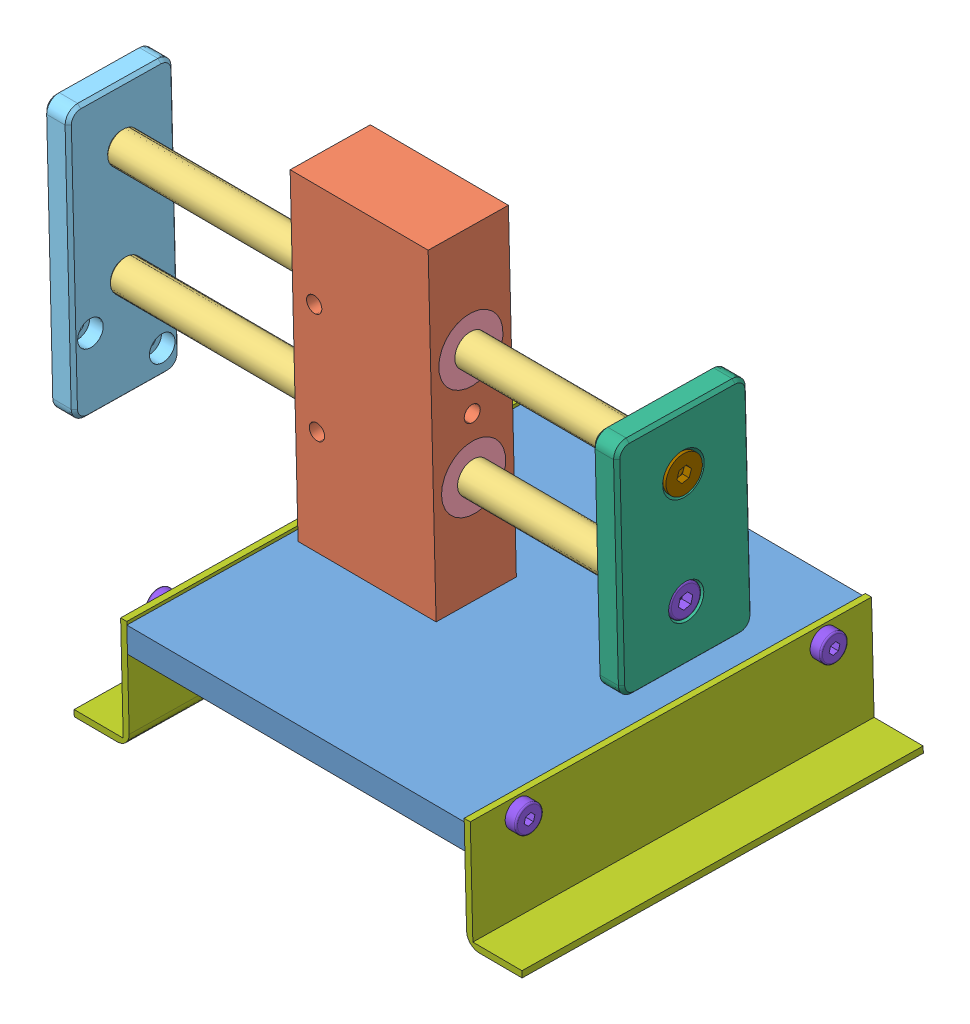
SolidWorks assembly cum s1, configuration Default. Lengths in mm.
Overall size (205.02 137.7 128.52).
22 component instances, 9 part files, 49 mates.
Components (placement in the parent):
- tam de lon-1: tam de lon [Default] at (119.0958 51.1975 54.0073) x (-0.999587 -0.017639 -0.022689) z (-0.022562 -0.007384 0.999718) size (110 8 125)
- con truot s1-2: con truot s1 [Default] at (88.5768 136.6703 53.9498) x (0.999587 0.017639 0.022689) z (0.022562 0.007384 -0.999718) size (45 102 25)
- chot dan huong-1: chot dan huong [Default] at (-2.2614 117.565 51.7586) x (0.021471 -0.983136 -0.181614) z (-0.019103 -0.182026 0.983108) size (10 175 10)
- chot dan huong-2: chot dan huong [Default] at (-1.6384 82.5714 51.5142) x (0.026236 -0.237789 -0.970963) z (0.011731 -0.971157 0.238153) size (10 175 10)
- bac lot-1: bac lot [Default] at (66.3976 118.7766 53.3171) x (0.028076 -0.767933 -0.639915) z (-0.006137 -0.640287 0.768111) size (20 12 20)
- bac lot-2: bac lot [Default] at (67.0207 83.783 53.0727) x (0.018145 -0.999587 -0.022287) z (-0.022287 -0.022689 0.999494) size (20 12 20)
- bac lot-3: bac lot [Default] at (111.379 119.5704 54.3381) x (-0.014484 -0.372719 0.927831) z (0.024823 -0.927776 -0.37231) size (20 12 20)
- bac lot-4: bac lot [Default] at (112.0021 84.5768 54.0937) x (-0.014484 -0.372719 0.927831) z (0.024823 -0.927776 -0.37231) size (20 12 20)
- ban canh truoc-1: ban canh truoc [Default] at (-1.8075 92.0697 51.5805) x (-0.022562 -0.007384 0.999718) z (0.017801 -0.999817 -0.006983) size (33 8 86)
- ban canh sau -S1-1: ban canh sau -S1 [Default] at (172.9778 103.155 55.607) x (-0.022562 -0.007384 0.999718) z (-0.017801 0.999817 0.006983) size (41 8 70)
- khoi do-1: khoi do [Default] at (173.7917 36.5109 117.6508) x (0.022562 0.007384 -0.999718) z (-0.999587 -0.017639 -0.022689) size (125 35 18)
- khoi do-2: khoi do [Default] at (64.9414 35.4633 -9.8487) x (-0.022562 -0.007384 0.999718) z (0.999587 0.017639 0.022689) size (125 35 18)
- socket head thin cap screw_din-2: socket head thin cap screw_din [DIN 7984 - M5 x 12 --- 9.6N] at (57.6203 45.7804 100.0932) x (0.999587 0.017639 0.022689) z (-0.022689 -0.0002 0.999743) size (15.5 8.5 8.5)
- socket head thin cap screw_din-3: socket head thin cap screw_din [DIN 7984 - M5 x 12 --- 9.6N] at (59.7637 46.4818 5.12) x (0.999587 0.017639 0.022689) z (-0.022689 -0.0002 0.999743) size (15.5 8.5 8.5)
- socket head thin cap screw_din-4: socket head thin cap screw_din [DIN 7984 - M5 x 12 --- 9.6N] at (180.7137 48.6161 7.8654) x (-0.999587 -0.017639 -0.022689) z (0.022689 -0.968916 -0.246346) size (15.5 8.5 8.5)
- socket head thin cap screw_din-5: socket head thin cap screw_din [DIN 7984 - M5 x 12 --- 9.6N] at (178.5703 47.9147 102.8386) x (-0.999587 -0.017639 -0.022689) z (0.022689 -0.968916 -0.246346) size (15.5 8.5 8.5)
- socket head thin cap screw_din-6: socket head thin cap screw_din [DIN 7984 - M5 x 12 --- 9.6N] at (108.0343 45.1492 61.2151) x (-0.017801 0.999817 0.006983) z (-0.006983 -0.007108 0.99995) size (15.5 8.5 8.5)
- socket head thin cap screw_din-7: socket head thin cap screw_din [DIN 7984 - M5 x 12 --- 9.6N] at (72.3876 44.6249 45.4025) x (-0.017801 0.999817 0.006983) z (-0.006983 -0.007108 0.99995) size (15.5 8.5 8.5)
- socket head thin cap screw_din-9: socket head thin cap screw_din [DIN 7984 - M6 x 14 --- 11N] at (181.0861 85.7958 55.6618) x (-0.999587 -0.017639 -0.022689) z (0.022689 -0.968916 -0.246346) size (18 10 10)
- socket head thin cap screw_din-10: socket head thin cap screw_din [DIN 7984 - M6 x 14 --- 11N] at (-9.4352 82.4339 51.3372) x (0.999587 0.017639 0.022689) z (-0.022689 -0.0002 0.999743) size (18 10 10)
- socket csink head cap screw 10642_din-2: socket csink head cap screw 10642_din [EN ISO 10642 - M6 x 16 - 16N] at (-10.478 117.42 51.5721) x (0.999587 0.017639 0.022689) z (-0.022678 -0.000819 0.999742) size (16 11.34 11.34)
- socket csink head cap screw 10642_din-3: socket csink head cap screw 10642_din [EN ISO 10642 - M6 x 16 - 16N] at (180.8829 120.7968 55.9157) x (-0.999587 -0.017639 -0.022689) z (0.021761 -0.980227 -0.196676) size (16 11.34 11.34)
Mates (geometry in assembly coordinates):
- Parallel5: parallel anti-aligned: plane of tam de lon-1 through (119.0958 51.1975 54.0073) normal (-0.017801 0.999817 0.006983); plane of con truot s1-2 through (90.1077 50.686 53.3493) normal (0.017801 -0.999817 -0.006983)
- Parallel6: parallel anti-aligned: plane of tam de lon-1 through (172.8053 43.7076 117.6817) normal (-0.022562 -0.007384 0.999718); plane of con truot s1-2 through (67.6142 66.3785 40.454) normal (0.022562 0.007384 -0.999718)
- Concentric3: concentric aligned: cylinder of tam de lon-1 through (72.2844 50.4239 45.443) axis (0.017801 -0.999817 -0.006983) radius 2.75; circle of con truot s1-2
- Coincident1: coincident anti-aligned: plane of tam de lon-1 through (119.0958 51.1975 54.0073) normal (-0.017801 0.999817 0.006983); plane of con truot s1-2 through (90.1077 50.686 53.3493) normal (0.017801 -0.999817 -0.006983)
- Concentric4: concentric anti-aligned: cylinder of con truot s1-2 through (41.408 118.3356 52.7498) axis (0.999587 0.017639 0.022689) radius 6; cylinder of chot dan huong-1 through (270.6258 122.3804 57.9528) axis (-0.999587 -0.017639 -0.022689) radius 5
- Concentric5: concentric anti-aligned: cylinder of con truot s1-2 through (42.031 83.342 52.5054) axis (0.999587 0.017639 0.022689) radius 6; cylinder of chot dan huong-2 through (271.2488 87.3868 57.7084) axis (-0.999587 -0.017639 -0.022689) radius 5
- Concentric6: concentric anti-aligned: cylinder of con truot s1-2 through (41.408 118.3356 52.7498) axis (0.999587 0.017639 0.022689) radius 6; cylinder of bac lot-1 through (78.3927 118.9883 53.5893) axis (-0.999587 -0.017639 -0.022689) radius 6
- Coincident2: coincident anti-aligned: plane of con truot s1-2 through (68.3968 118.8119 53.3624) normal (-0.999587 -0.017639 -0.022689); plane of bac lot-1 through (68.3968 118.8119 53.3624) normal (0.999587 0.017639 0.022689)
- Concentric7: concentric anti-aligned: cylinder of con truot s1-2 through (42.031 83.342 52.5054) axis (0.999587 0.017639 0.022689) radius 6; cylinder of bac lot-2 through (79.0157 83.9947 53.3449) axis (-0.999587 -0.017639 -0.022689) radius 6
- Coincident3: coincident anti-aligned: plane of con truot s1-2 through (69.0199 83.8183 53.1181) normal (-0.999587 -0.017639 -0.022689); plane of bac lot-2 through (69.0199 83.8183 53.1181) normal (0.999587 0.017639 0.022689)
- Concentric8: concentric aligned: cylinder of con truot s1-2 through (41.408 118.3356 52.7498) axis (0.999587 0.017639 0.022689) radius 6; cylinder of bac lot-3 through (99.384 119.3587 54.0658) axis (0.999587 0.017639 0.022689) radius 6
- Coincident4: coincident anti-aligned: plane of con truot s1-2 through (109.3799 119.5351 54.2927) normal (0.999587 0.017639 0.022689); plane of bac lot-3 through (109.3799 119.5351 54.2927) normal (-0.999587 -0.017639 -0.022689)
- Concentric9: concentric aligned: cylinder of con truot s1-2 through (42.031 83.342 52.5054) axis (0.999587 0.017639 0.022689) radius 6; cylinder of bac lot-4 through (100.0071 84.3651 53.8214) axis (0.999587 0.017639 0.022689) radius 6
- Coincident5: coincident anti-aligned: plane of con truot s1-2 through (110.0029 84.5415 54.0483) normal (0.999587 0.017639 0.022689); plane of bac lot-4 through (110.0029 84.5415 54.0483) normal (-0.999587 -0.017639 -0.022689)
- Concentric10: concentric aligned: cylinder of chot dan huong-1 through (270.6258 122.3804 57.9528) axis (-0.999587 -0.017639 -0.022689) radius 5; cylinder of ban canh truoc-1 through (-2.2614 117.565 51.7586) axis (-0.999587 -0.017639 -0.022689) radius 3.3
- Concentric11: concentric aligned: cylinder of chot dan huong-2 through (271.2488 87.3868 57.7084) axis (-0.999587 -0.017639 -0.022689) radius 5; cylinder of ban canh truoc-1 through (-1.6384 82.5714 51.5142) axis (-0.999587 -0.017639 -0.022689) radius 3.3
- Coincident6: coincident anti-aligned: plane of chot dan huong-1 through (-2.2614 117.565 51.7586) normal (-0.999587 -0.017639 -0.022689); plane of ban canh truoc-1 through (-1.8075 92.0697 51.5805) normal (0.999587 0.017639 0.022689)
- Coincident7: coincident anti-aligned: plane of chot dan huong-2 through (-1.6384 82.5714 51.5142) normal (-0.999587 -0.017639 -0.022689); plane of ban canh truoc-1 through (-1.8075 92.0697 51.5805) normal (0.999587 0.017639 0.022689)
- Concentric12: concentric anti-aligned: cylinder of chot dan huong-1 through (270.6258 122.3804 57.9528) axis (-0.999587 -0.017639 -0.022689) radius 5; cylinder of ban canh sau -S1-1 through (172.6663 120.6518 55.7292) axis (0.999587 0.017639 0.022689) radius 3.3
- Concentric13: concentric anti-aligned: cylinder of chot dan huong-2 through (271.2488 87.3868 57.7084) axis (-0.999587 -0.017639 -0.022689) radius 5; cylinder of ban canh sau -S1-1 through (173.2893 85.6582 55.4848) axis (0.999587 0.017639 0.022689) radius 3.3
- Coincident8: coincident anti-aligned: plane of chot dan huong-1 through (172.6663 120.6518 55.7292) normal (0.999587 0.017639 0.022689); plane of ban canh sau -S1-1 through (172.9778 103.155 55.607) normal (-0.999587 -0.017639 -0.022689)
- Coincident9: coincident anti-aligned: plane of chot dan huong-2 through (173.2893 85.6582 55.4848) normal (0.999587 0.017639 0.022689); plane of ban canh sau -S1-1 through (172.9778 103.155 55.607) normal (-0.999587 -0.017639 -0.022689)
- Parallel7: parallel aligned: plane of tam de lon-1 through (65.671 42.6903 -9.7789) normal (-0.999587 -0.017639 -0.022689); plane of khoi do-1 through (176.0884 18.6354 -7.4646) normal (-0.999587 -0.017639 -0.022689)
- Parallel8: parallel aligned: plane of tam de lon-1 through (119.0958 51.1975 54.0073) normal (-0.017801 0.999817 0.006983); plane of khoi do-1 through (175.4654 53.629 -7.2202) normal (-0.017801 0.999817 0.006983)
- Concentric14: concentric aligned: cylinder of tam de lon-1 through (160.2221 48.2545 7.4003) axis (0.999587 0.017639 0.022689) radius 2.5; cylinder of khoi do-1 through (52.2667 46.3495 4.9498) axis (0.999587 0.017639 0.022689) radius 2.5
- Coincident10: coincident anti-aligned: plane of tam de lon-1 through (175.6256 44.6306 -7.2831) normal (0.999587 0.017639 0.022689); plane of khoi do-1 through (176.0884 18.6354 -7.4646) normal (-0.999587 -0.017639 -0.022689)
- Parallel9: parallel anti-aligned: plane of tam de lon-1 through (65.671 42.6903 -9.7789) normal (-0.999587 -0.017639 -0.022689); plane of khoi do-2 through (63.3136 15.7721 115.0043) normal (0.999587 0.017639 0.022689)
- Parallel10: parallel anti-aligned: plane of tam de lon-1 through (119.0958 51.1975 54.0073) normal (-0.017801 0.999817 0.006983); plane of khoi do-2 through (63.3136 15.7721 115.0043) normal (0.017801 -0.999817 -0.006983)
- Concentric15: concentric aligned: cylinder of tam de lon-1 through (80.2552 46.8434 5.5851) axis (-0.999587 -0.017639 -0.022689) radius 2.5; cylinder of khoi do-2 through (188.2106 48.7484 8.0356) axis (-0.999587 -0.017639 -0.022689) radius 2.5
- Coincident11: coincident anti-aligned: plane of tam de lon-1 through (65.671 42.6903 -9.7789) normal (-0.999587 -0.017639 -0.022689); plane of khoi do-2 through (63.3136 15.7721 115.0043) normal (0.999587 0.017639 0.022689)
- Concentric16: concentric aligned: cylinder of khoi do-2 through (186.0672 48.047 103.0088) axis (-0.999587 -0.017639 -0.022689) radius 2.5; cylinder of socket head thin cap screw_din-2 through (25.8834 45.2204 99.3728) axis (-0.999587 -0.017639 -0.022689) radius 4.25
- Coincident12: coincident anti-aligned: plane of khoi do-2 through (61.2788 17.7365 114.9729) normal (-0.999587 -0.017639 -0.022689); plane of socket head thin cap screw_din-2 through (61.0438 50.0915 100.1718) normal (0.999587 0.017639 0.022689)
- Concentric17: concentric aligned: cylinder of khoi do-2 through (188.2106 48.7484 8.0356) axis (-0.999587 -0.017639 -0.022689) radius 2.5; cylinder of socket head thin cap screw_din-3 through (28.0268 45.9218 4.3996) axis (-0.999587 -0.017639 -0.022689) radius 4.25
- Coincident13: coincident anti-aligned: plane of khoi do-2 through (61.2788 17.7365 114.9729) normal (-0.999587 -0.017639 -0.022689); plane of socket head thin cap screw_din-3 through (63.1872 50.7929 5.1986) normal (0.999587 0.017639 0.022689)
- Concentric18: concentric aligned: cylinder of khoi do-1 through (52.2667 46.3495 4.9498) axis (0.999587 0.017639 0.022689) radius 2.5; cylinder of socket head thin cap screw_din-4 through (212.4506 49.1762 8.5858) axis (0.999587 0.017639 0.022689) radius 4.25
- Coincident14: coincident anti-aligned: plane of khoi do-1 through (178.052 20.6703 -7.4053) normal (0.999587 0.017639 0.022689); plane of socket head thin cap screw_din-4 through (177.2901 49.6031 3.6681) normal (-0.999587 -0.017639 -0.022689)
- Concentric19: concentric aligned: cylinder of khoi do-1 through (50.1234 45.6481 99.9231) axis (0.999587 0.017639 0.022689) radius 2.5; cylinder of socket head thin cap screw_din-5 through (210.3072 48.4747 103.559) axis (0.999587 0.017639 0.022689) radius 4.25
- Coincident15: coincident anti-aligned: plane of khoi do-1 through (178.052 20.6703 -7.4053) normal (0.999587 0.017639 0.022689); plane of socket head thin cap screw_din-5 through (175.1467 48.9017 98.6413) normal (-0.999587 -0.017639 -0.022689)
- Concentric20: concentric aligned: cylinder of tam de lon-1 through (107.972 48.6485 61.2395) axis (0.017801 -0.999817 -0.006983) radius 5; cylinder of socket head thin cap screw_din-6 through (108.5995 13.405 60.9934) axis (0.017801 -0.999817 -0.006983) radius 4.25
- Coincident16: coincident anti-aligned: plane of tam de lon-1 through (107.972 48.6485 61.2395) normal (0.017801 -0.999817 -0.006983); plane of socket head thin cap screw_din-6 through (103.7228 48.5731 61.2093) normal (-0.017801 0.999817 0.006983)
- Concentric21: concentric aligned: cylinder of tam de lon-1 through (72.2844 50.4239 45.443) axis (0.017801 -0.999817 -0.006983) radius 2.75; cylinder of socket head thin cap screw_din-7 through (72.9528 12.8807 45.1808) axis (0.017801 -0.999817 -0.006983) radius 4.25
- Coincident17: coincident anti-aligned: plane of tam de lon-1 through (72.3253 48.1243 45.4269) normal (0.017801 -0.999817 -0.006983); plane of socket head thin cap screw_din-7 through (68.0761 48.0489 45.3967) normal (-0.017801 0.999817 0.006983)
- Concentric22: concentric aligned: cylinder of ban canh sau -S1-1 through (177.0877 85.7253 55.5711) axis (0.999587 0.017639 0.022689) radius 5.5; cylinder of socket head thin cap screw_din-9 through (212.823 86.3558 56.3822) axis (0.999587 0.017639 0.022689) radius 5
- Coincident18: coincident anti-aligned: plane of ban canh sau -S1-1 through (177.0877 85.7253 55.5711) normal (0.999587 0.017639 0.022689); plane of socket head thin cap screw_din-9 through (177.1759 86.9591 50.7265) normal (-0.999587 -0.017639 -0.022689)
- Concentric23: concentric aligned: cylinder of ban canh truoc-1 through (-5.4368 82.5044 51.428) axis (-0.999587 -0.017639 -0.022689) radius 5.5; cylinder of socket head thin cap screw_din-10 through (-41.1721 81.8738 50.6168) axis (-0.999587 -0.017639 -0.022689) radius 5
- Coincident19: coincident anti-aligned: plane of ban canh truoc-1 through (-5.4368 82.5044 51.428) normal (-0.999587 -0.017639 -0.022689); plane of socket head thin cap screw_din-10 through (-5.525 87.5036 51.427) normal (0.999587 0.017639 0.022689)
- Coincident20: coincident aligned: cone of ban canh truoc-1 through (-7.0595 117.4804 51.6497) axis (0.999587 0.017639 0.022689); cone of socket csink head cap screw 10642_din-2 through (-9.4285 117.4386 51.5959) axis (0.999587 0.017639 0.022689)
- Coincident21: coincident aligned: cone of ban canh sau -S1-1 through (177.4643 120.7365 55.8381) axis (-0.999587 -0.017639 -0.022689); cone of socket csink head cap screw 10642_din-3 through (179.8333 120.7783 55.8919) axis (-0.999587 -0.017639 -0.022689)
- LimitDistance1: limit distance = 61.3125 mm anti-aligned: plane of ban canh sau -S1-1 through (172.9778 103.155 55.607) normal (-0.999587 -0.017639 -0.022689); plane of con truot s1-2 through (112.0316 66.9877 66.468) normal (0.999587 0.017639 0.022689)
